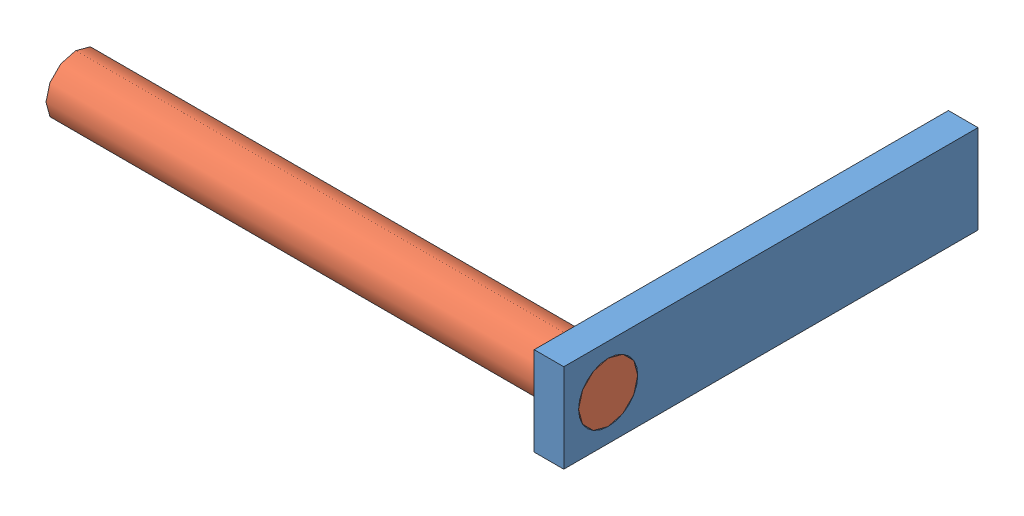
SolidWorks assembly L-Part 1-3, configuration Default. Lengths in mm.
Overall size (180 30 140).
2 component instances, 2 part files, 2 mates.
Components (placement in the parent):
- Rectangular Beam 1-3-1: Rectangular Beam 1-3 [Default] at origin size (10 30 140)
- Cylindrical Rod 1-3-1: Cylindrical Rod 1-3 [Default] at (-170 0 0) size (180 20 20)
Mates (geometry in assembly coordinates):
- Concentric1: concentric aligned: cylinder of Rectangular Beam 1-3-1 through (10 0 0) axis (-1 0 0) radius 10; cylinder of Cylindrical Rod 1-3-1 through (10 0 0) axis (-1 0 0) radius 10
- Coincident1: coincident aligned: plane of Rectangular Beam 1-3-1 through (10 0 0) normal (1 0 0); plane of Cylindrical Rod 1-3-1 through (10 0 0) normal (1 0 0)
